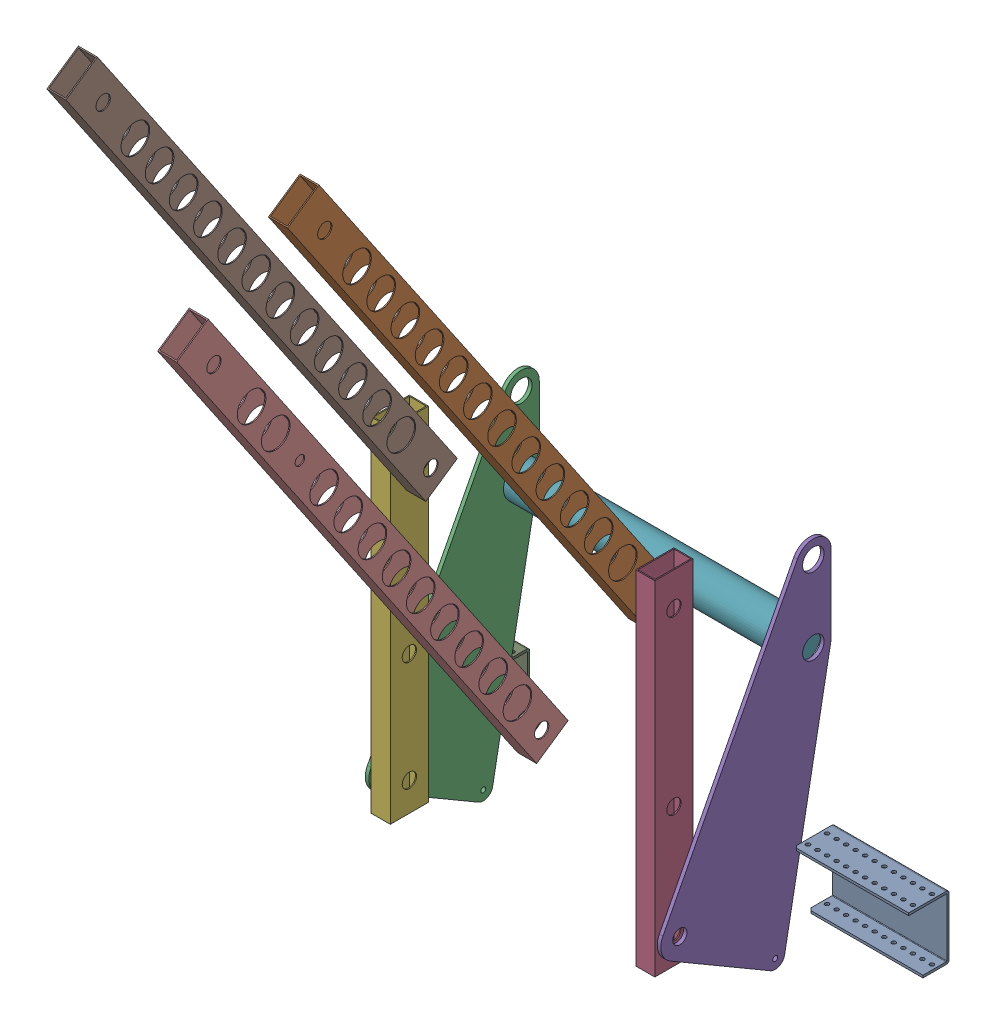
SolidWorks assembly lowered_intake, configuration Default. Lengths in mm.
Overall size (711.2 1172.51 697.46).
11 component instances, 6 part files, 0 mates.
Components (placement in the parent):
- am-xxxx AM14U4 End Plate Square Short-1: am-xxxx AM14U4 End Plate Square Short [Default] at (37.0064 27.8264 -342.9772) x (1 0 0) z (0 -1 0) size (152.4 53.98 84.58)
- lift_arm_Default_As Machined_.3-1: lift_arm_Default_As Machined_.3 [Default] at (59.2314 1133.9253 323.8249) x (0 -0.826099 -0.563525) z (-1 0 0) size (850.9 50.8 25.4)
- intake_3_1-1: intake_3_1 [Default] at (8.5469 -69.4829 -403.1249) size (393.82 520.7 236.69)
  - intake_side_rev3SLDPRT.2-1: intake_side_rev3SLDPRT.2 [Default] at (-293.803 45.2132 287.1603) size (4.76 471.49 227.01)
  - end_link_Default_As Machined_.6-1: end_link_Default_As Machined_.6 [Default] at (79.2595 108.7132 261.7603) size (25.4 457.2 50.8)
  - intake_side_rev3SLDPRT.2-2: intake_side_rev3SLDPRT.2 [Default] at (95.1345 45.2132 287.1603) size (4.76 471.49 227.01)
  - end_link_Default_As Machined_.6-2: end_link_Default_As Machined_.6 [Default] at (-273.1655 108.7132 261.7603) size (25.4 457.2 50.8)
  - intake_roller.4-1: intake_roller.4 [Default] at (-293.9207 391.2882 83.9603) x (1 0 0) z (0 0.77759 0.628772) size (381 47.62 47.62)
- lift_arm_Default_As Machined_.3-2: lift_arm_Default_As Machined_.3 [Default] at (-236.0436 1133.9253 323.8249) x (0 -0.826099 -0.563525) z (-1 0 0) size (850.9 50.8 25.4)
- am-xxxx AM14U4 End Plate Square Short-2: am-xxxx AM14U4 End Plate Square Short [Default] at (-521.7936 27.8264 -342.9772) x (1 0 0) z (0 -1 0) size (152.4 53.98 84.58)
- lower_lift_arm_Default_As Machined_.5-1: lower_lift_arm_Default_As Machined_.5 [Default] at (-88.4061 905.3253 323.8249) x (0 -0.826099 -0.563525) z (1 0 0) size (850.9 50.8 25.4)
